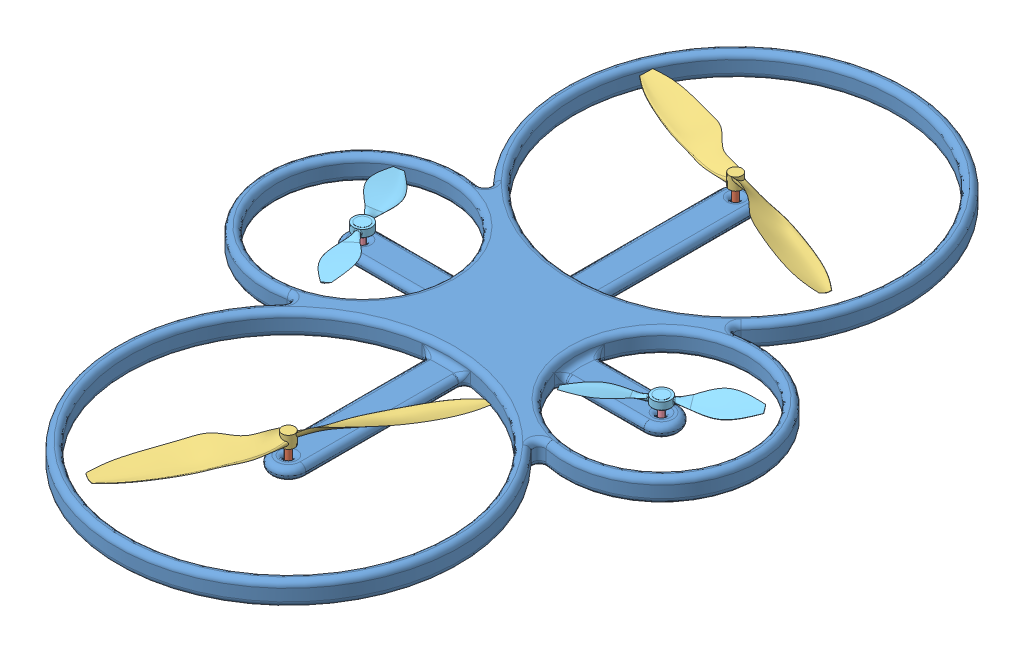
SolidWorks assembly Assem1, configuration Default. Lengths in mm.
Overall size (423.23 229.29 677.23).
9 component instances, 5 part files, 8 mates.
Components (placement in the parent):
- Shroud-1: Shroud [Default] at origin size (423.23 20 677.23)
- PropShaft-1: PropShaft [Default] at (0 -5 -191.6158) size (5 15 5)
- PropShaft-2: PropShaft [Default] at (0 -5 191.6158) size (5 15 5)
- 5x3L L-1: 5x3L L [Default] at (-2.5879 23.243 -192.6125) x (0.301957 0.023402 -0.953034) z (0.496479 -0.857289 0.136252) size (33.17 221.5 133.67)
- 5x3L L-2: 5x3L L [Default] at (-1.3006 23.243 194.0651) x (-0.909828 0.023402 -0.414325) z (0.194942 -0.857289 -0.476501) size (33.17 221.5 133.67)
- SmallPropShaft-1: SmallPropShaft [Default] at (128.1158 -5 0) size (5 15 5)
- SmallPropShaft-2: SmallPropShaft [Default] at (-128.1158 -5 0) size (5 15 5)
- User Library-7_5 inch prop (1)-1: User Library-7_5 inch prop (1) [Default] at (128.1158 10 0) x (0.56442 0 0.825488) z (0 1 0) size (32.63 127.03 9.17)
- User Library-7_5 inch prop (1)-2: User Library-7_5 inch prop (1) [Default] at (-128.1158 10 0) x (-0.911281 0 0.411784) z (0 1 0) size (32.63 127.03 9.17)
Mates (geometry in assembly coordinates):
- Coincident1: coincident aligned: circle of Shroud-1; circle of PropShaft-2
- Coincident2: coincident aligned: circle of Shroud-1; circle of PropShaft-1
- Coincident3: coincident anti-aligned: circle of PropShaft-1; circle of 5x3L L-1
- Coincident4: coincident anti-aligned: circle of PropShaft-2; circle of 5x3L L-2
- Coincident5: coincident aligned: circle of Shroud-1; circle of SmallPropShaft-1
- Coincident6: coincident aligned: circle of Shroud-1; circle of SmallPropShaft-2
- Coincident7: coincident aligned: circle of SmallPropShaft-1; circle of User Library-7_5 inch prop (1)-1
- Coincident8: coincident aligned: circle of SmallPropShaft-2; circle of User Library-7_5 inch prop (1)-2
